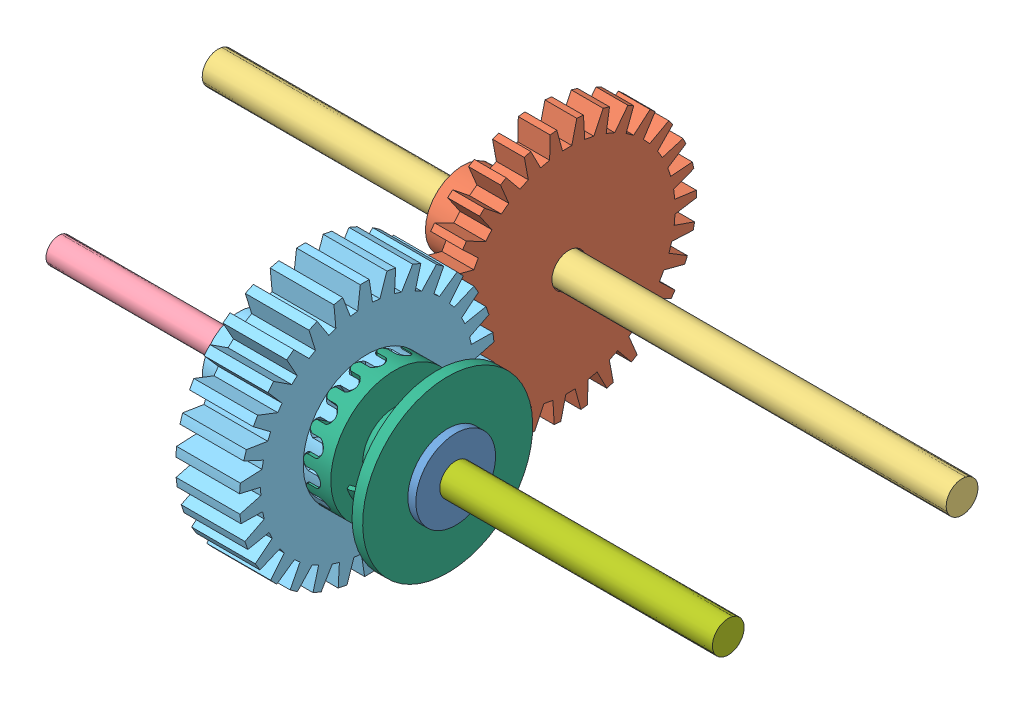
SolidWorks assembly clutch_only, configuration Default. Lengths in mm.
Overall size (70 32.88 52.52).
7 component instances, 7 part files, 14 mates.
Components (placement in the parent):
- bushing-1: bushing [Default] at (39.8495 35.8914 94.8254) x (0 -0.967546 0.252694) z (0 0.252694 0.967546) size (7.5 5 7.5)
- drive_gear-1: drive_gear [Default] at (29.2495 36.2802 72.8289) x (0 0.981314 -0.192411) z (0 0.192411 0.981314) size (23.93 10 24)
- drive_shaft-2: drive_shaft [Default] at (-3.7505 36.2802 72.8289) x (1 0 0) z (0 0.886639 -0.462462) size (70 3 3)
- clutch_shaft-1: clutch_shaft [Default] at (3.2495 35.8914 94.8254) x (1 0 0) z (0 -0.648262 -0.761418) size (23 2.4 2.4)
- clutch-1: clutch [Default] at (26.2495 35.8914 94.8254) x (1 0 0) z (0 -0.857363 -0.514712) size (13.63 24 23.94)
- spool-1: spool [Default] at (39.8495 35.8914 94.8254) x (-1 0 0) z (0 0.732661 0.680593) size (7.63 16 16)
- spool_shaft-1: spool_shaft [Default] at (26.2495 35.8914 94.8254) x (1 0 0) z (0 0.9581 -0.286434) size (40 3 3)
Mates (geometry in assembly coordinates):
- Coincident1: coincident anti-aligned: plane of bushing-1 through (39.8495 35.8914 94.8254) normal (-1 0 0); plane of spool-1 through (39.8495 35.8914 94.8254) normal (1 0 0)
- Concentric1: concentric aligned: cylinder of drive_gear-1 through (29.2495 36.2802 72.8289) axis (-1 0 0) radius 1.6; cylinder of drive_shaft-2 through (66.2495 36.2802 72.8289) axis (-1 0 0) radius 1.5
- LimitDistance1: limit distance = 1.6 mm anti-aligned: plane of clutch-1 through (32.2495 35.8914 94.8254) normal (1 0 0); plane of spool-1 through (33.8495 35.8914 94.8254) normal (-1 0 0)
- Concentric2: concentric aligned: cylinder of bushing-1 through (40.5995 35.8914 94.8254) axis (-1 0 0) radius 1.5; cylinder of spool_shaft-1 through (66.2495 35.8914 94.8254) axis (-1 0 0) radius 1.5
- Concentric3: concentric anti-aligned: cylinder of bushing-1 through (35.5995 35.8914 94.8254) axis (1 0 0) radius 2.25; cylinder of spool-1 through (39.8495 35.8914 94.8254) axis (-1 0 0) radius 2.25
- Concentric4: concentric aligned: cylinder of clutch-1 through (26.2495 35.8914 94.8254) axis (-1 0 0) radius 1.2; cylinder of spool_shaft-1 through (66.2495 35.8914 94.8254) axis (-1 0 0) radius 1.5
- Concentric5: concentric aligned: cylinder of clutch_shaft-1 through (26.2495 35.8914 94.8254) axis (-1 0 0) radius 1.2; cylinder of clutch-1 through (26.2495 35.8914 94.8254) axis (-1 0 0) radius 1.2
- Distance1: distance = 6 mm anti-aligned: plane of clutch_shaft-1 through (26.2495 35.8914 94.8254) normal (1 0 0); plane of clutch-1 through (20.2495 35.8914 94.8254) normal (-1 0 0)
- Coincident3: coincident aligned: plane of drive_shaft-2 through (66.2495 36.2802 72.8289) normal (1 0 0); plane of spool_shaft-1 through (66.2495 35.8914 94.8254) normal (1 0 0)
- Distance2: distance = 22 mm: cylinder of spool_shaft-1 through (66.2495 35.8914 94.8254) axis (-1 0 0) radius 1.5; cylinder of drive_shaft-2 through (66.2495 36.2802 72.8289) axis (-1 0 0) radius 1.5
- Distance3: distance = 8.6 mm anti-aligned: plane of spool-1 through (34.8495 35.8914 94.8254) normal (1 0 0); plane of spool_shaft-1 through (26.2495 35.8914 94.8254) normal (-1 0 0)
- Distance4: distance = 37 mm aligned: plane of drive_gear-1 through (29.2495 36.2802 72.8289) normal (1 0 0); plane of drive_shaft-2 through (66.2495 36.2802 72.8289) normal (1 0 0)
- GearMate1: gear = 24 : 24 mm: cylinder of clutch-1 through (32.2495 35.8914 94.8254) axis (-1 0 0) radius 12; cylinder of drive_gear-1 through (26.2495 36.2802 72.8289) axis (1 0 0) radius 12
- GearMate3: gear = 12 : 12 mm: circle of clutch-1; circle of spool-1
